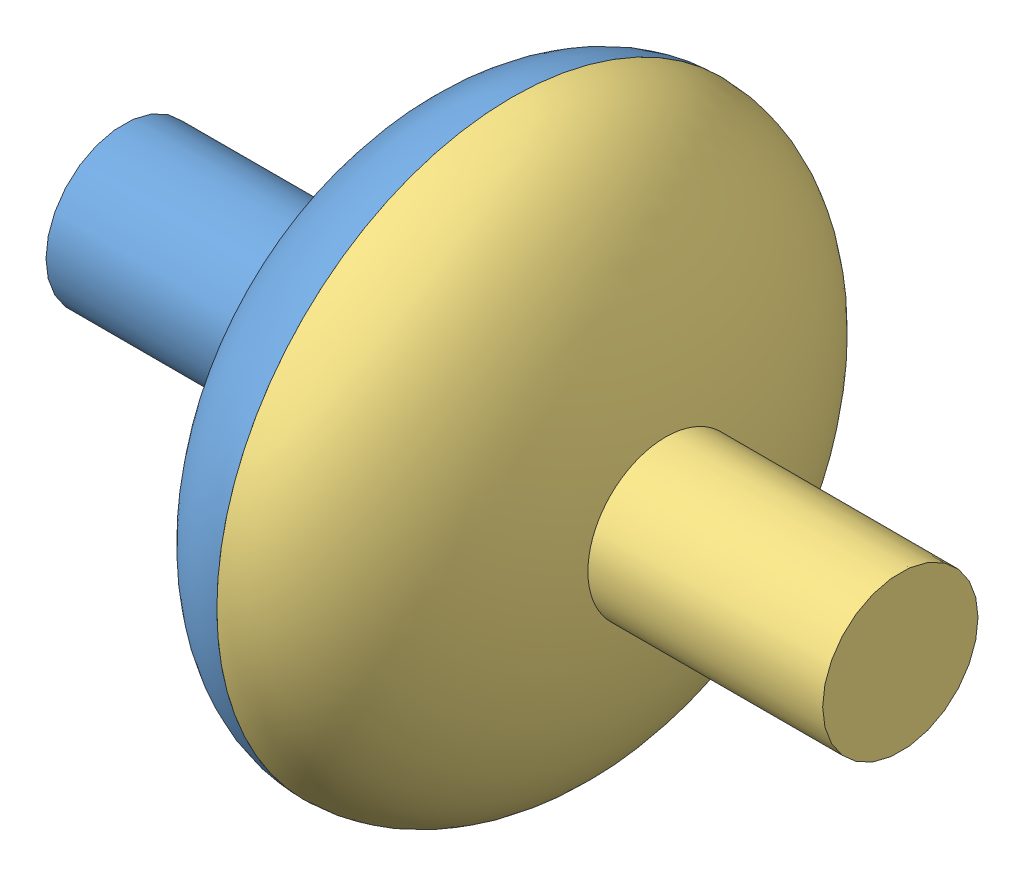
SolidWorks assembly Spinner_Low, configuration Default. Lengths in mm.
Overall size (127 96.52 96.52).
3 component instances, 3 part files, 6 mates.
Components (placement in the parent):
- Spinner_Left-1: Spinner_Left [Default] at (55.8798 40.0998 70.589) size (67.95 96.52 96.52)
- DiceLow-1: DiceLow [Default] at (55.8886 5.7153 53.5515) x (0.999999 -0.000781 -0.000912) z (0.0012 0.650573 0.759442) size (12.7 10.41 11)
- Spinner_Right-1: Spinner_Right [Default] at (55.8798 40.0998 70.589) size (64.49 96.52 96.52)
Mates (geometry in assembly coordinates):
- Coincident1: coincident: point of Spinner_Left-1; point of DiceLow-1
- Coincident2: coincident: line of Spinner_Left-1 through (49.3641 8.3075 56.5775) axis (0.49896 -0.563804 -0.658152); line of DiceLow-1 through (55.8798 0.9451 47.983) axis (-0.49896 0.563804 0.658152)
- Coincident3: coincident anti-aligned: plane of Spinner_Left-1 through (55.8798 28.6862 80.3665) normal (0 0.759443 -0.650574); plane of DiceLow-1 through (55.8886 5.7153 53.5515) normal (0 -0.759443 0.650574)
- Coincident4: coincident: plane of Spinner_Left-1 through (60.3248 82.5078 65.7378) normal (0 -0.974636 0.223795); plane of Spinner_Right-1 through (78.7809 82.5078 65.7378) normal (0 0.974636 -0.223795)
- Coincident5: coincident: plane of Spinner_Left-1 through (60.3248 83.9931 65.3967) normal (0 0.223795 0.974636); plane of Spinner_Right-1 through (78.7809 83.9931 65.3967) normal (0 -0.223795 -0.974636)
- Coincident6: coincident anti-aligned: plane of Spinner_Left-1 through (55.8798 40.0998 70.589) normal (1 0 0); plane of Spinner_Right-1 through (74.2089 40.0998 70.589) normal (-1 0 0)
